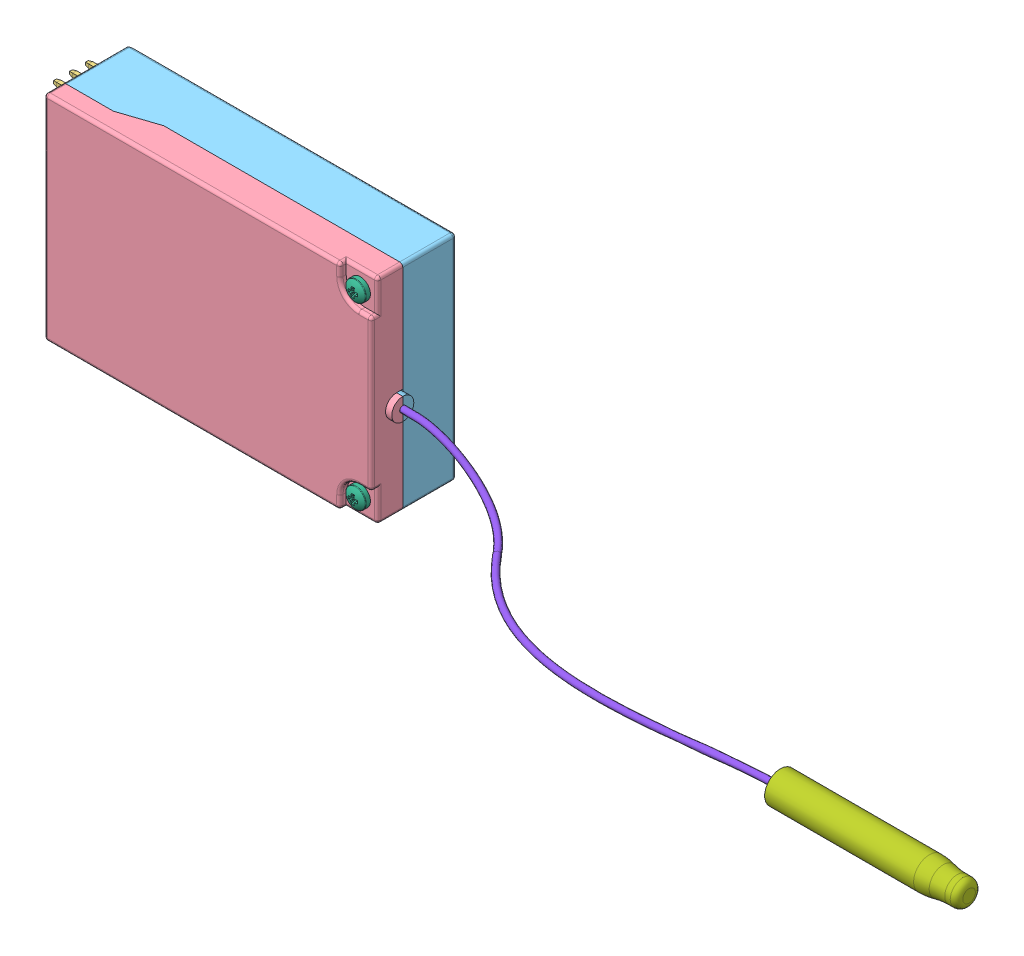
SolidWorks assembly TURNIGY - Receiver 9X, configuration Défaut. Lengths in mm.
Overall size (156 34 24.61).
19 component instances, 8 part files, 25 mates.
Components (placement in the parent):
- Planche 1-1: Planche 1 [Défaut] at (0 0 5.25) size (32 31 1.5)
- Planche 2-1: Planche 2 [Défaut] at (-16.75 0 6.75) x (0 1 0) z (1 0 0) size (31 10.5 1.5)
- Broche Vertical 1x3-1: Broche Vertical 1x3 [Default] at (-18.75 14.25 9.29) x (0 0 1) z (-1 0 0) size (7.62 2.5 11)
- Broche Vertical 1x3-10: Broche Vertical 1x3 [Default] at (-18.75 -14.25 9.29) x (0 0 1) z (-1 0 0) size (7.62 2.5 11)
- Broche Vertical 1x3-11: Broche Vertical 1x3 [Default] at (-18.75 11.25 9.29) x (0 0 1) z (-1 0 0) size (7.62 2.5 11)
- Broche Vertical 1x3-12: Broche Vertical 1x3 [Default] at (-18.75 8.25 9.29) x (0 0 1) z (-1 0 0) size (7.62 2.5 11)
- Broche Vertical 1x3-13: Broche Vertical 1x3 [Default] at (-18.75 5.25 9.29) x (0 0 1) z (-1 0 0) size (7.62 2.5 11)
- Broche Vertical 1x3-14: Broche Vertical 1x3 [Default] at (-18.75 2.25 9.29) x (0 0 1) z (-1 0 0) size (7.62 2.5 11)
- Broche Vertical 1x3-15: Broche Vertical 1x3 [Default] at (-18.75 -11.25 9.29) x (0 0 1) z (-1 0 0) size (7.62 2.5 11)
- Broche Vertical 1x3-16: Broche Vertical 1x3 [Default] at (-18.75 -8.25 9.29) x (0 0 1) z (-1 0 0) size (7.62 2.5 11)
- Broche Vertical 1x3-17: Broche Vertical 1x3 [Default] at (-18.75 -5.25 9.29) x (0 0 1) z (-1 0 0) size (7.62 2.5 11)
- Broche Vertical 1x3-18: Broche Vertical 1x3 [Default] at (-18.75 -2.25 9.29) x (0 0 1) z (-1 0 0) size (7.62 2.5 11)
- Coque inférieur-1: Coque inférieur [Défaut] at (3.5 0 14.5) x (1 0 0) z (0 0 -1) size (53 34 5)
- Coque Supérieur-1: Coque Supérieur [Défaut] at (3.5 0 12.5) x (1 0 0) z (0 0 -1) size (53.03 34 13.03)
- pan head cross recess screw_din-2: pan head cross recess screw_din [ISO 7045 - M1.6 x 10 - Z --- 10N] at (26.75 -14.25 14.8) x (0 0 -1) z (1 0 0) size (11.25 3.2 3.2)
- pan head cross recess screw_din-3: pan head cross recess screw_din [ISO 7045 - M1.6 x 10 - Z --- 10N] at (26.75 14.25 14.8) x (0 0 -1) z (1 0 0) size (11.25 3.2 3.2)
- Antenne-1: Antenne [Défaut] at (112.5 -14.5 20) x (0 1 0) z (0 0 -1) size (5 30 5)
- Cable_3-SA_Récepteur 9X-1: Cable_3-SA_Récepteur 9X [Défaut] at origin size (74 15.25 15.57)
  - Cble^Cable_3-SA_Récepteur 9X-1: Cble^Cable_3-SA_Récepteur 9X [Défaut] at origin size (74 15.25 15.57) (virtual)
Mates (geometry in assembly coordinates):
- Coïncidente1: coincident anti-aligned: plane of Planche 1-1 through (-16 15.5 6) normal (-1 0 0); plane of Planche 2-1 through (-16 0 6.75) normal (1 0 0)
- Distance2: distance = 6 mm aligned: plane of Planche 1-1 through (0 0 6) normal (0 0 1); plane of Planche 2-1 through (-16 -15.5 12) normal (0 0 1)
- Coïncidente4: coincident aligned: plane of Planche 1-1 through (-16 -15.5 6) normal (0 -1 0); plane of Planche 2-1 through (-16 -15.5 12) normal (0 -1 0)
- Coïncidente32: coincident aligned: plane of Broche Vertical 1x3-1 through (-20 15.1464 2.94) normal (0 0 -1); plane of Broche Vertical 1x3-10 through (-20 -13.3536 2.94) normal (0 0 -1)
- Coïncidente41: coincident aligned: plane of Broche Vertical 1x3-1 through (-20 15.5 5.48) normal (-1 0 0); plane of Broche Vertical 1x3-10 through (-20 -13 5.48) normal (-1 0 0)
- Coïncidente42: coincident aligned: plane of Broche Vertical 1x3-1 through (-20 15.5 5.8336) normal (0 1 0); plane of Planche 2-1 through (-16 15.5 12) normal (0 1 0)
- Coïncidente46: coincident: plane of Planche 2-1 through (-17.5 0 6.75) normal (-1 0 0); line of Broche Vertical 1x3-1 through (-17.5 15.5 7.6664) axis (0 0 -1)
- Distance3: distance = 0.32 mm anti-aligned: plane of Broche Vertical 1x3-1 through (-15 13.93 6.43) normal (0 0 -1); plane of Planche 2-1
- Coïncidente48: coincident aligned: plane of Planche 2-1 through (-16 -15.5 12) normal (0 -1 0); plane of Broche Vertical 1x3-10 through (-20 -15.5 5.8336) normal (0 -1 0)
- Coïncidente49: coincident aligned: plane of Coque inférieur-1 through (-22.5 17 9.5) normal (0 1 0); plane of Coque Supérieur-1 through (-22.5 17 0) normal (0 1 0)
- Coïncidente50: coincident aligned: plane of Coque inférieur-1 through (29.5 -17 9.5) normal (1 0 0); plane of Coque Supérieur-1 through (29.5 -17 0) normal (1 0 0)
- Coïncidente57: coincident anti-aligned: plane of Broche Vertical 1x3-10 through (-20 -13 8.02) normal (-1 0 0); plane of Coque Supérieur-1 through (-20 0 12.5) normal (1 0 0)
- Coïncidente59: coincident anti-aligned: plane of Planche 1-1 through (-16 -15.5 6) normal (0 -1 0); plane of Coque Supérieur-1 through (-22.5 -15.5 0) normal (0 1 0)
- Coïncidente62: coincident anti-aligned: plane of Coque inférieur-1 through (-8.5 0 9.5) normal (-0.316228 0 -0.948683); plane of Coque Supérieur-1 through (-14.5 -17 11.5) normal (0.316228 0 0.948683)
- Distance4: distance = 3.25 mm aligned: plane of Planche 2-1; plane of Coque Supérieur-1 through (30.501 0 3.5) normal (0 0 1)
- Coaxiale8: concentric anti-aligned: cylinder of Coque inférieur-1 through (26.75 -14.25 18.6569) axis (0 0 -1) radius 1; cylinder of pan head cross recess screw_din-2 through (26.75 -14.25 40.2) axis (0 0 1) radius 1.6
- Coïncidente69: coincident anti-aligned: plane of Coque inférieur-1 through (27.5 -15 13.5) normal (0 0 1); plane of pan head cross recess screw_din-2 through (26.75 -13.45 13.5) normal (0 0 -1)
- Coaxiale9: concentric anti-aligned: cylinder of Coque inférieur-1 through (26.75 14.25 18.6569) axis (0 0 -1) radius 1; cylinder of pan head cross recess screw_din-3 through (26.75 14.25 40.2) axis (0 0 1) radius 1.6
- Coïncidente70: coincident anti-aligned: plane of Coque inférieur-1 through (27.5 15 13.5) normal (0 0 1); plane of pan head cross recess screw_din-3 through (26.75 15.05 13.5) normal (0 0 -1)
- Coïncidente71: coincident aligned: plane of Planche 1-1 through (0 0 5.25) normal (0 1 0); plane of assembly through (0 0 0) normal (0 1 0)
- Coïncidente72: coincident aligned: plane of Planche 1-1 through (0 0 5.25) normal (1 0 0); plane of assembly through (0 0 0) normal (1 0 0)
- Coïncidente73: coincident anti-aligned: plane of Coque Supérieur-1 through (3.5 0 0) normal (0 0 -1); plane of assembly through (0 0 0) normal (0 0 1)
- Distance8: distance = 2.5 mm anti-aligned: plane of Antenne-1; plane of Coque Supérieur-1 through (-22.5 -17 0) normal (0 -1 0)
- Distance9: distance = 100 mm anti-aligned: plane of Antenne-1 through (100 -15 20) normal (-1 0 0); plane of assembly through (0 0 0) normal (1 0 0)
- Distance10: distance = 20 mm anti-aligned: plane of assembly through (0 0 0) normal (0 0 1); plane of Antenne-1 through (112.5 -14.5 20) normal (0 0 -1)
